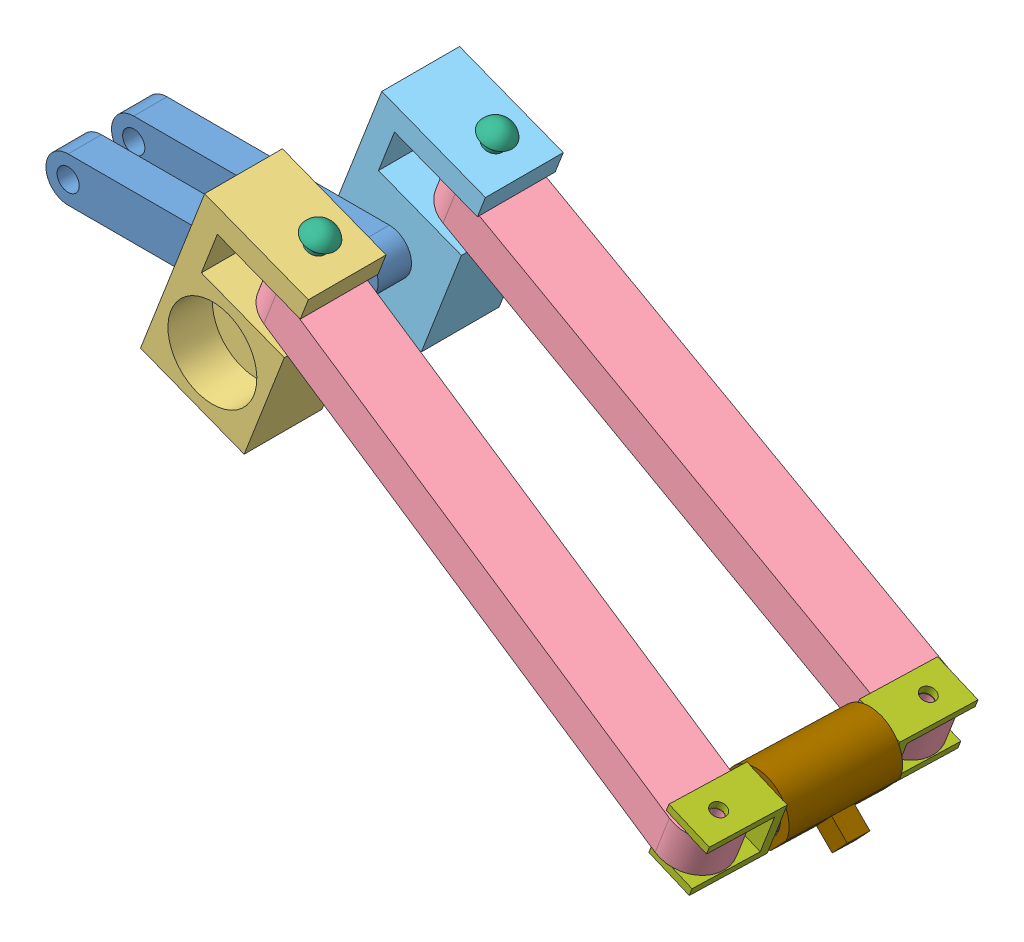
SolidWorks assembly 装配, configuration 默认. Lengths in mm.
Overall size (382.39 144.56 150.98).
13 component instances, 9 part files, 24 mates.
Components (placement in the parent):
- 连杆1-1: 连杆1 [默认] at (37.2808 15.5669 75.0769) size (120 20 15)
- 转轴1-2-1: 转轴1-2 [默认] at (137.2808 5.5669 100.7407) x (0 0 -1) z (0.985543 -0.169427 0) size (65 10 10)
- 连杆1-2: 连杆1 [默认] at (37.2808 15.5669 45.5734) size (120 20 15)
- 方型连接-2: 方型连接 [默认] at (122.9835 37.9025 125.1769) x (0 0 -1) z (0.360764 0.932657 0) size (35 50 80)
- 连杆2-1: 连杆2 [默认] at (365.6185 -33.4557 65.229) x (0.094807 -0.036673 -0.99482) z (0.927826 -0.358896 0.101653) size (30 17.72 260)
- 连杆2-2: 连杆2 [默认] at (360.6006 -52.8384 127.1384) x (-0.145513 0.056286 0.987754) z (0.921236 -0.356346 0.15602) size (30 17.72 260)
- 方型连接左-1: 方型连接左 [默认] at (104.9452 -8.7304 10.4734) x (0 0 1) z (-0.360764 -0.932657 0) size (35 50 80)
- cup head nib bolts gb-2: cup head nib bolts gb [GB_FASTENER_BOLT_CHNB M8X30-N] at (170.122 62.7499 27.9734) x (-0.360764 -0.932657 0) z (0.796683 -0.308168 -0.519932) size (35.28 14.33 14.33)
- cup head nib bolts gb-3: cup head nib bolts gb [GB_FASTENER_BOLT_CHNB M8X30-N] at (170.122 62.7499 107.6769) x (-0.360764 -0.932657 0) z (-0.890493 0.344454 0.297278) size (35.28 14.33 14.33)
- 条状连接1-1: 条状连接1 [默认] at (386.0075 -38.9904 88.7465) x (-0.02206 0.008533 0.99972) z (0.932396 -0.360663 0.023653) size (120 25 20)
- 条状连接1-2: 条状连接1 [默认] at (385.5668 -38.8199 108.7209) x (0.02206 -0.008533 -0.99972) z (-0.932396 0.360663 -0.023653) size (120 25 20)
- 圆棍-1: 圆棍 [默认] at (381.8315 -50.7776 73.6307) x (-0.02206 0.008533 0.99972) z (0.994803 -0.099234 0.022799) size (50 20 20)
- 中心轴承-1: 中心轴承 [默认] at (381.8271 -50.7759 73.8306) x (-0.02206 0.008533 0.99972) z (0.726987 -0.686302 0.0219) size (50 30 39.14)
Mates (geometry in assembly coordinates):
- 平行1: parallel aligned: line of 连杆1-1 through (37.2808 15.5669 75.0769) axis (1 0 0); line of 连杆1-2 through (37.2808 15.5669 45.5734) axis (1 0 0)
- 同心2: concentric anti-aligned: cylinder of 连杆1-1 through (137.2808 5.5669 90.0769) axis (0 0 -1) radius 5; cylinder of 转轴1-2-1 through (137.2808 5.5669 35.7407) axis (0 0 1) radius 5
- 同心3: concentric anti-aligned: cylinder of 转轴1-2-1 through (137.2808 5.5669 35.7407) axis (0 0 1) radius 5; cylinder of 连杆1-2 through (137.2808 5.5669 60.5734) axis (0 0 -1) radius 5
- 同心4: concentric anti-aligned: cylinder of 转轴1-2-1 through (137.2808 5.5669 35.7407) axis (0 0 1) radius 5; cylinder of 方型连接-2 through (137.2808 5.5669 90.1769) axis (0 0 -1) radius 3.3
- 同心10: concentric aligned: cylinder of 转轴1-2-1 through (137.2808 5.5669 35.7407) axis (0 0 1) radius 5; cylinder of 方型连接左-1 through (137.2808 5.5669 45.4734) axis (0 0 1) radius 3.3
- 同心13: concentric aligned: cylinder of cup head nib bolts gb-2 through (181.4804 92.114 27.9734) axis (0.360764 0.932657 0) radius 4; cylinder of 方型连接左-1 through (166.4494 53.2554 27.9734) axis (0.360764 0.932657 0) radius 3.3
- 同心14: concentric aligned: cylinder of 连杆2-1 through (162.8057 43.8356 27.9734) axis (0.360764 0.932657 0) radius 3.3; cylinder of cup head nib bolts gb-2 through (181.4804 92.114 27.9734) axis (0.360764 0.932657 0) radius 4
- 同心16: concentric aligned: circle of cup head nib bolts gb-3; cylinder of 方型连接-2 through (166.4494 53.2554 107.6769) axis (0.360764 0.932657 0) radius 3.3
- 同心17: concentric anti-aligned: cylinder of 连杆2-2 through (156.4111 27.3043 107.6769) axis (-0.360764 -0.932657 0) radius 3.3; cylinder of cup head nib bolts gb-3 through (181.4804 92.114 107.6769) axis (0.360764 0.932657 0) radius 4
- 距离1: distance = 0.1 mm anti-aligned: plane of 方型连接-2 through (176.8316 38.5174 125.1769) normal (-0.360764 -0.932657 0); plane of 连杆2-2 through (395.0224 -45.989 131.819) normal (0.360764 0.932657 0)
- 距离3: distance = 0.1 mm anti-aligned: plane of 连杆1-1 through (37.2808 15.5669 90.0769) normal (0 0 1); plane of 方型连接-2 through (122.9835 37.9025 90.1769) normal (0 0 -1)
- 距离4: distance = 0.1 mm anti-aligned: plane of 方型连接左-1 through (104.9452 -8.7304 45.4734) normal (0 0 1); plane of 连杆1-2 through (37.2808 15.5669 45.5734) normal (0 0 -1)
- 距离5: distance = 0.1 mm anti-aligned: plane of cup head nib bolts gb-3 through (167.5223 52.7332 111.4961) normal (-0.360764 -0.932657 0); plane of 方型连接-2 through (133.8064 65.8822 125.1769) normal (0.360764 0.932657 0)
- 距离7: distance = 0.1 mm anti-aligned: plane of 方型连接左-1 through (133.8064 65.8822 10.4734) normal (0.360764 0.932657 0); plane of cup head nib bolts gb-2 through (164.4736 53.9124 24.5565) normal (-0.360764 -0.932657 0)
- 距离8: distance = 0.1 mm anti-aligned: plane of 连杆2-1 through (393.0631 -45.2311 68.2785) normal (0.360764 0.932657 0); plane of 方型连接左-1 through (176.8316 38.5174 10.4734) normal (-0.360764 -0.932657 0)
- 同心18: concentric aligned: circle of 连杆2-1; circle of 条状连接1-1
- 距离10: distance = 0.5 mm anti-aligned: plane of 条状连接1-2 through (386.9392 -62.4032 128.3482) normal (0.360764 0.932657 0); plane of 连杆2-2 through (388.6278 -62.5203 131.819) normal (-0.360764 -0.932657 0)
- 同心19: concentric anti-aligned: circle of 条状连接1-2; circle of 连杆2-2
- 同心32: concentric anti-aligned: cylinder of 条状连接1-1 through (381.9257 -50.8141 69.3616) axis (0.02206 -0.008533 -0.99972) radius 3.3; cylinder of 条状连接1-2 through (380.6295 -50.3126 128.1058) axis (-0.02206 0.008533 0.99972) radius 3.3
- 同心33: concentric aligned: cylinder of 条状连接1-2 through (380.6295 -50.3126 128.1058) axis (-0.02206 0.008533 0.99972) radius 3.3; cylinder of 圆棍-1 through (380.7285 -50.351 123.6167) axis (-0.02206 0.008533 0.99972) radius 3.3
- 距离11: distance = 0.1 mm anti-aligned: plane of 圆棍-1 through (380.7285 -50.351 123.6167) normal (-0.02206 0.008533 0.99972); plane of 条状连接1-2 through (404.1165 -45.9952 124.1956) normal (0.02206 -0.008533 -0.99972)
- 距离12: distance = 0.12 mm anti-aligned: plane of 条状连接1-1 through (367.4579 -31.8151 73.2717) normal (-0.02206 0.008533 0.99972); plane of 圆棍-1 through (381.8315 -50.7776 73.6307) normal (0.02206 -0.008533 -0.99972)
- 同心34: concentric aligned: cylinder of 圆棍-1 through (380.7285 -50.351 123.6167) axis (0.02206 -0.008533 -0.99972) radius 10; cylinder of 中心轴承-1 through (380.7241 -50.3493 123.8167) axis (0.02206 -0.008533 -0.99972) radius 11
- 距离13: distance = 0.1 mm anti-aligned: plane of 条状连接1-2 through (404.1165 -45.9952 124.1956) normal (0.02206 -0.008533 -0.99972); plane of 中心轴承-1 through (380.7241 -50.3493 123.8167) normal (-0.02206 0.008533 0.99972)
